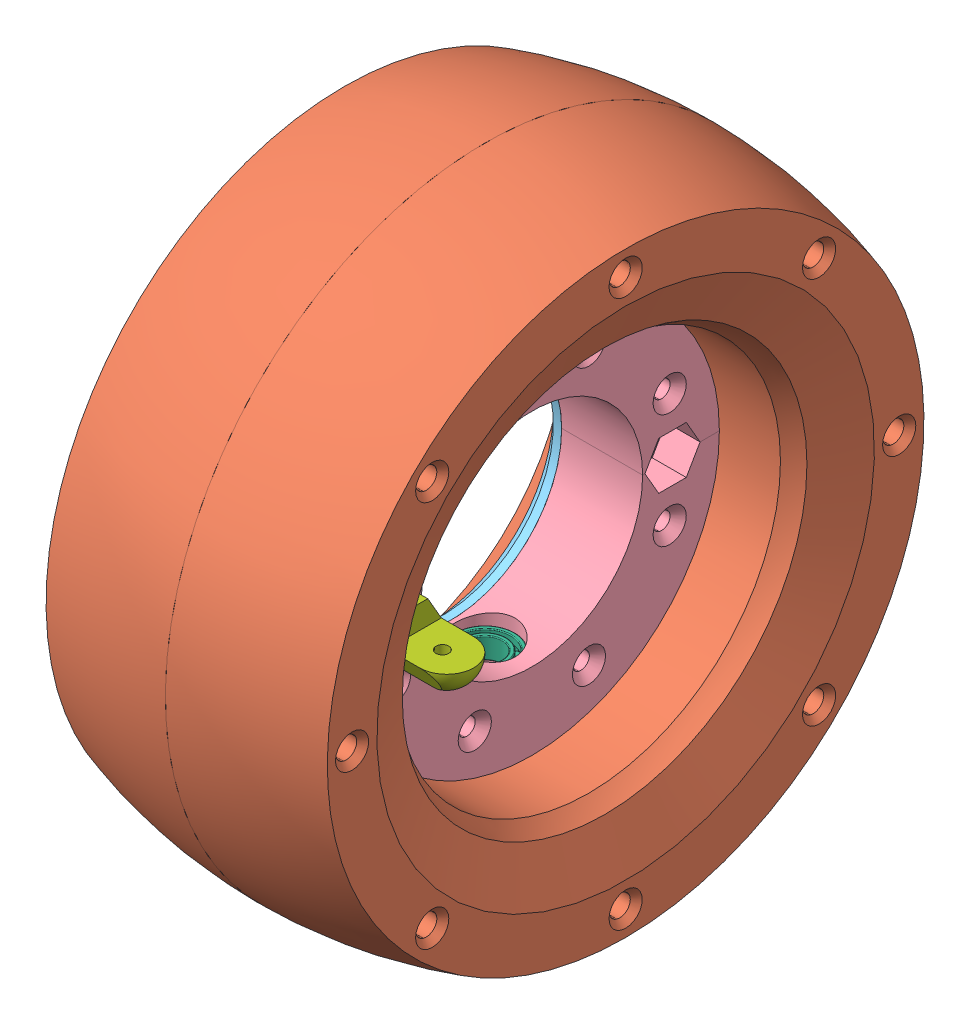
SolidWorks assembly Rad-Vorne, configuration Links. Lengths in mm.
Overall size (33 75 75).
12 component instances, 7 part files, 31 mates.
Components (placement in the parent):
- Kugellager - 61808 6808-1: Kugellager - 61808 6808 [Standard] x (0 0 -1) z (1 0 0) size (52 52 7)
- Rad-Vorne-Korpus-1: Rad-Vorne-Korpus [Außen] x (0 0 1) z (-1 0 0) size (75 75 16.5)
- Lager-Abstandsscheibe-1: Lager-Abstandsscheibe [Außen] at (-3.75 0 0) x (0 0 1) z (-1 0 0) size (52 52 0.5)
- Rad-Vorne-Aufnahme-1: Rad-Vorne-Aufnahme [Mit Sechskant] at origin size (9.5 22 44)
- Rad-Vorne-Innenkranz-1: Rad-Vorne-Innenkranz [Standard] x (0 0 1) z (-1 0 0) size (44 44 4.65)
- Lager-Abstandsscheibe-3: Lager-Abstandsscheibe [Innen] at (-3.75 0 0) x (0 0 -1) z (1 0 0) size (43 43 0.5)
- Kugellager - MR74-1: Kugellager - MR74 [Standard] at (0 15.25 0) x (1 0 0) z (0 -1 0) size (7 7 2.5)
- Kugellager - MR74-3: Kugellager - MR74 [Standard] at (0 -15.25 0) x (1 0 0) z (0 1 0) size (7 7 2.5)
- Rad-Vorne-Aufnahme-3: Rad-Vorne-Aufnahme [Mit Sechskant] x (1 0 0) z (0 0 -1) size (9.5 22 44)
- Lager-Abstandsscheibe-4: Lager-Abstandsscheibe [Außen] at (3.75 0 0) x (0 0 -1) z (1 0 0) size (52 52 0.5)
- Rad-Vorne-Korpus-3: Rad-Vorne-Korpus [Innen] x (0 0 1) z (1 0 0) size (75 75 16.5)
- Gelenkbolzen-1: Gelenkbolzen [M3] at (1.5 0 16.5) x (0 -1 0) z (-1 0 0) size (5.5 6.35 13.68)
Mates (geometry in assembly coordinates):
- Deckungsgleich2: coincident aligned: plane of Kugellager - 61808 6808-1 through (0 0 0) normal (1 0 0); plane of assembly through (0 0 0) normal (1 0 0)
- Deckungsgleich3: coincident aligned: plane of Kugellager - 61808 6808-1; plane of assembly through (0 0 0) normal (0 1 0)
- Deckungsgleich4: coincident anti-aligned: plane of Kugellager - 61808 6808-1 through (0 0 0) normal (0 0 -1); plane of assembly through (0 0 0) normal (0 0 1)
- Deckungsgleich5: coincident aligned: plane of Rad-Vorne-Korpus-1 through (0 0 0) normal (0 0 1); plane of assembly through (0 0 0) normal (0 0 1)
- Deckungsgleich6: coincident aligned: plane of Rad-Vorne-Korpus-1; plane of assembly through (0 0 0) normal (0 1 0)
- Deckungsgleich7: coincident anti-aligned: plane of Rad-Vorne-Korpus-1 through (0 0 0) normal (-1 0 0); plane of assembly through (0 0 0) normal (1 0 0)
- Deckungsgleich8: coincident anti-aligned: plane of Kugellager - 61808 6808-1 through (-3.5 0 0) normal (-1 0 0); plane of Lager-Abstandsscheibe-1 through (-3.5 0 0) normal (1 0 0)
- Konzentrisch1: concentric aligned: cylinder of Kugellager - 61808 6808-1 through (0 0 0) axis (1 0 0) radius 20; cylinder of Lager-Abstandsscheibe-1 through (-4 0 0) axis (1 0 0) radius 24.5
- Deckungsgleich9: coincident aligned: plane of Lager-Abstandsscheibe-1; plane of assembly through (0 0 0) normal (0 1 0)
- Deckungsgleich13: coincident aligned: plane of Rad-Vorne-Aufnahme-1 through (0 0 0) normal (1 0 0); plane of assembly through (0 0 0) normal (1 0 0)
- Deckungsgleich14: coincident aligned: plane of Rad-Vorne-Aufnahme-1 through (0 0 0) normal (0 1 0); plane of assembly through (0 0 0) normal (0 1 0)
- Deckungsgleich15: coincident aligned: plane of Rad-Vorne-Aufnahme-1 through (0 0 0) normal (0 0 1); plane of assembly through (0 0 0) normal (0 0 1)
- Deckungsgleich16: coincident anti-aligned: plane of Rad-Vorne-Innenkranz-1 through (0 0 0) normal (-1 0 0); plane of assembly through (0 0 0) normal (1 0 0)
- Deckungsgleich17: coincident aligned: plane of Rad-Vorne-Innenkranz-1; plane of assembly through (0 0 0) normal (0 1 0)
- Deckungsgleich18: coincident aligned: plane of Rad-Vorne-Innenkranz-1 through (0 0 0) normal (0 0 1); plane of assembly through (0 0 0) normal (0 0 1)
- Deckungsgleich19: coincident anti-aligned: plane of Kugellager - 61808 6808-1 through (-3.5 0 0) normal (-1 0 0); plane of Lager-Abstandsscheibe-3 through (-3.5 0 0) normal (1 0 0)
- Deckungsgleich20: coincident anti-aligned: plane of Lager-Abstandsscheibe-3 through (-3.75 0 0) normal (0 0 -1); plane of assembly through (0 0 0) normal (0 0 1)
- Deckungsgleich21: coincident aligned: plane of Lager-Abstandsscheibe-3; plane of assembly through (0 0 0) normal (0 1 0)
- Deckungsgleich22: coincident anti-aligned: plane of Rad-Vorne-Aufnahme-1 through (0 16.5 0) normal (0 -1 0); plane of Kugellager - MR74-1 through (0 16.5 0) normal (0 1 0)
- Konzentrisch2: concentric anti-aligned: cylinder of Rad-Vorne-Aufnahme-1 through (0 -16.5 0) axis (0 1 0) radius 3.5; cylinder of Kugellager - MR74-1 through (0 15.25 0) axis (0 -1 0) radius 3.5
- Deckungsgleich23: coincident aligned: plane of Kugellager - MR74-1; plane of assembly through (0 0 0) normal (1 0 0)
- Deckungsgleich24: coincident anti-aligned: plane of Kugellager - 61808 6808-1 through (3.5 0 0) normal (1 0 0); plane of Lager-Abstandsscheibe-4 through (3.5 0 0) normal (-1 0 0)
- Konzentrisch3: concentric anti-aligned: cylinder of Kugellager - 61808 6808-1 through (0 0 0) axis (1 0 0) radius 26; cylinder of Lager-Abstandsscheibe-4 through (4 0 0) axis (-1 0 0) radius 26
- Deckungsgleich25: coincident aligned: plane of Lager-Abstandsscheibe-4; plane of assembly through (0 0 0) normal (0 1 0)
- Deckungsgleich26: coincident aligned: plane of Rad-Vorne-Korpus-3; plane of assembly through (0 0 0) normal (0 0 1)
- Deckungsgleich27: coincident anti-aligned: plane of Rad-Vorne-Korpus-3; plane of assembly through (0 0 0) normal (0 1 0)
- Deckungsgleich28: coincident aligned: plane of Rad-Vorne-Korpus-3 through (0 0 0) normal (1 0 0); plane of assembly through (0 0 0) normal (1 0 0)
- Deckungsgleich29: coincident anti-aligned: plane of Rad-Vorne-Aufnahme-1 through (1.5 0 0) normal (1 0 0); plane of Gelenkbolzen-1 through (1.5 0 16.5) normal (-1 0 0)
- Lenkung-L: coincident anti-aligned: plane of Gelenkbolzen-1; plane of assembly through (0 0 0) normal (0 1 0)
- Deckungsgleich32: coincident anti-aligned: line of Rad-Vorne-Aufnahme-1 through (5.5 0 16.5) axis (1 0 0); line of Gelenkbolzen-1 through (7.5 0 16.5) axis (-1 0 0)
- Lenkung-R: coincident aligned: plane of Gelenkbolzen-1; plane of assembly through (0 0 0) normal (0 1 0)
